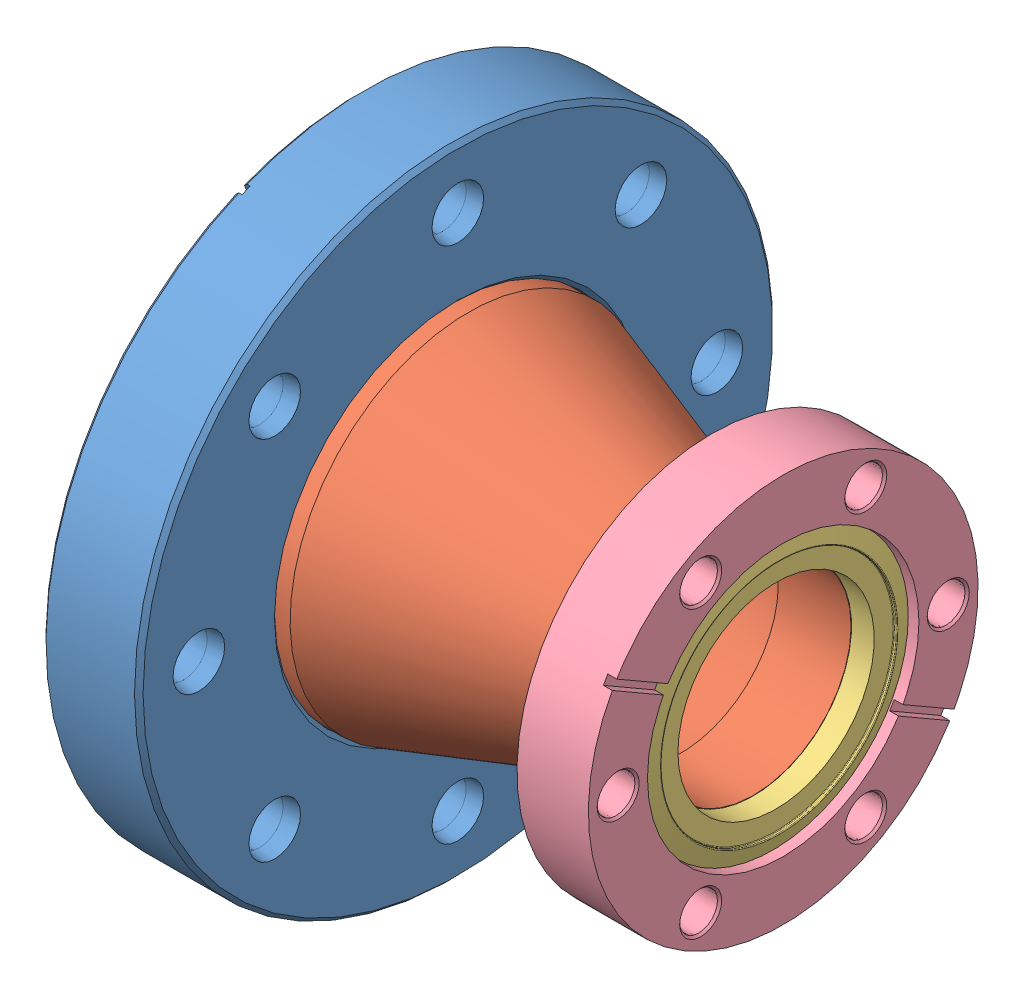
SolidWorks assembly 402032, configuration Default. Lengths in mm.
Overall size (75.16 113.54 113.54).
4 component instances, 4 part files, 7 mates.
Components (placement in the parent):
- 110021-1: 110021 [Default] at (37.7911 57.2108 86.4005) size (17.27 113.54 113.54)
- 402505-1: 402505 [Default] at (47.3161 57.2108 86.4005) x (1 0 0) z (0 0.348935 0.937147) size (60.32 63.5 63.5)
- 910014-1: 910014 [Default] at (112.2893 57.2108 86.4005) x (-1 0 0) z (0 0 1) size (6.91 48.06 48.06)
- 915002-1: 915002 [Default] at (112.9497 57.2108 86.4005) x (-1 0 0) z (0 1 0) size (12.7 69.34 69.34)
Mates (geometry in assembly coordinates):
- Concentric1: concentric aligned: cylinder of 110021-1 through (37.7911 57.2108 86.4005) axis (-1 0 0) radius 31.877; cylinder of 402505-1 through (47.3161 57.2108 86.4005) axis (-1 0 0) radius 31.75
- Coincident1: coincident anti-aligned: plane of 110021-1 through (47.3161 87.3733 86.4005) normal (1 0 0); plane of 402505-1 through (47.3161 57.2108 86.4005) normal (-1 0 0)
- Concentric2: concentric aligned: cylinder of 910014-1 through (112.2893 57.2108 86.4005) axis (1 0 0) radius 24.0284; cylinder of 915002-1 through (112.9497 57.2108 86.4005) axis (1 0 0) radius 24.1554
- Coincident3: coincident anti-aligned: plane of 910014-1 through (105.3297 33.1824 86.4005) normal (-1 0 0); plane of 915002-1 through (105.3297 40.7235 97.3861) normal (1 0 0)
- Concentric3: concentric anti-aligned: cylinder of 402505-1 through (47.3161 57.2108 86.4005) axis (-1 0 0) radius 19.05; cylinder of 910014-1 through (112.2893 57.2108 86.4005) axis (1 0 0) radius 17.4625
- Coincident4: coincident anti-aligned: plane of 402505-1 through (107.6411 75.0635 79.7533) normal (1 0 0); plane of 910014-1 through (107.6411 38.0338 86.4005) normal (-1 0 0)
- Parallel1: parallel aligned: plane of 915002-1 through (112.9497 57.2108 86.4005) normal (0 1 0)
